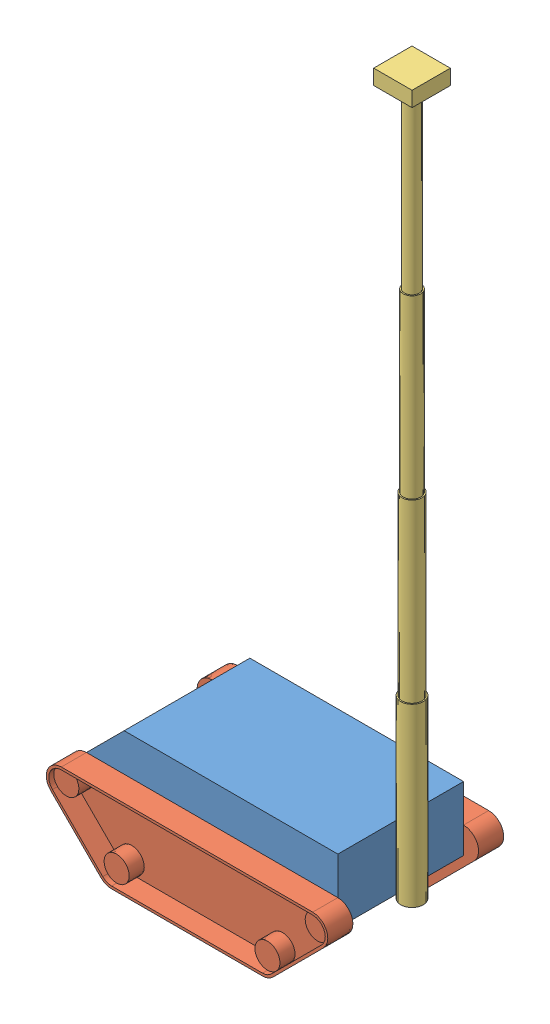
SolidWorks assembly Assemblage1, configuration Défaut. Lengths in mm.
Overall size (1257.42 3075 700).
4 component instances, 3 part files, 8 mates.
Components (placement in the parent):
- pièce caisse simple-1: pièce caisse simple [Défaut] at (-802.8452 44.1484 -250) size (1000 360 500)
- pièce chenille simple-1: pièce chenille simple [Défaut] at (-490.5606 2.1947 250) size (1120 320 100)
- pièce chenille simple-2: pièce chenille simple [Défaut] at (394.636 2.1947 -250) x (-1 0 0) z (0 0 -1) size (1120 320 100)
- Poteau déplié simple-1: Poteau déplié simple [Défaut] at (493.6228 670.4643 3.7343) x (-0.704647 0 0.709558) z (0 -1 0) size (215.58 215.58 2860)
Mates (geometry in assembly coordinates):
- Coïncidente1: coincident anti-aligned: plane of pièce caisse simple-1 through (-47.9623 -781.3621 250) normal (0 0 1); plane of pièce chenille simple-1 through (-47.9623 -990.6926 250) normal (0 0 -1)
- Coïncidente2: coincident: point of pièce caisse simple-1; point of pièce chenille simple-1
- Coïncidente7: coincident anti-aligned: plane of pièce caisse simple-1 through (-47.9623 -781.3621 -250) normal (0 0 -1); plane of pièce chenille simple-2 through (-47.9623 -990.6926 -250) normal (0 0 1)
- Parallèle1: parallel aligned: line of pièce caisse simple-1 through (452.0377 225.4643 -250) axis (-1 0 0); line of pièce chenille simple-2 through (452.0377 75.4643 -250) axis (-1 0 0)
- Coïncidente9: coincident: point of pièce caisse simple-1; point of pièce chenille simple-2
- Coaxiale2: concentric anti-aligned: circle of ?
- Parallèle4: parallel anti-aligned: line of pièce caisse simple-1 through (452.0377 225.4643 250) axis (0 0 -1); line of Poteau déplié simple-1 through (420.7219 2913.9844 -76.1394) axis (0 0 1)
- Coïncidente19: coincident: moEndPointRef_w of pièce caisse simple-1; circle of Poteau déplié simple-1
